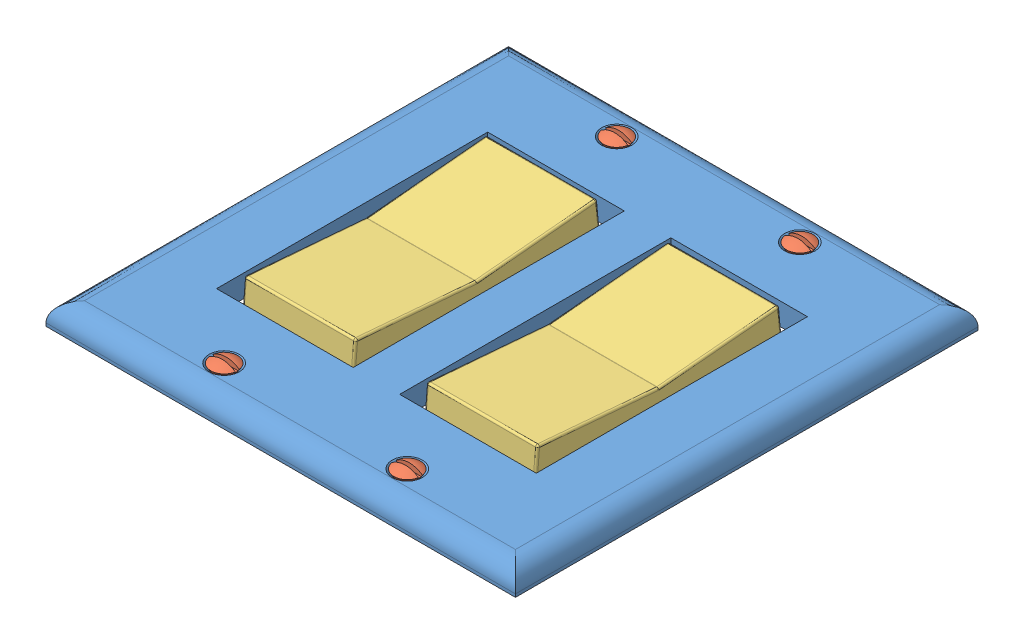
SolidWorks assembly rocker-switch, configuration Default. Lengths in mm.
Overall size (116 20.38 114.3).
7 component instances, 3 part files, 17 mates.
Components (placement in the parent):
- switchplate-1: switchplate [Default] at (-25.7009 60.0885 119.6547) size (116 5.5 114.3)
- screw-1: screw [Default] at (5.0495 56.6846 195.5169) x (0 -1 0) z (0 0 1) size (13.64 6.52 6.6)
- screw-2: screw [Default] at (-40.2005 56.6846 195.5169) x (0 -1 0) z (0 0 1) size (13.64 6.52 6.6)
- screw-3: screw [Default] at (5.0495 56.6846 98.5169) x (0 -1 0) z (0 0 1) size (13.64 6.52 6.6)
- screw-4: screw [Default] at (-40.2005 56.6846 98.5169) x (0 -1 0) z (0 0 1) size (13.64 6.52 6.6)
- rocker-3: rocker [Default] at (-8.7005 68.2721 117.0828) x (0 0.089515 -0.995986) z (1 0 0) size (60.87 12.79 27.5)
- rocker-4: rocker [Default] at (-26.4505 68.0995 176.5789) x (0 0.083761 0.996486) z (-1 0 0) size (60.87 12.79 27.5)
Mates (geometry in assembly coordinates):
- Distance1: distance = 15 mm: plane of ? through (-48.2755 80.5885 104.57) normal (0 1 0); plane of switchplate-1 through (-25.7009 65.5885 119.6547) normal (0 1 0)
- Distance2: distance = 1.8 mm anti-aligned: plane of switchplate-1 through (-23.3255 65.5885 113.3318) normal (-1 0 0); plane of ? through (-48.2755 67.6218 104.57) normal (1 0 0)
- Distance3: distance = 1.8 mm: plane of ? through (-9.1755 67.6218 145.4487) normal (-1 0 0); plane of switchplate-1 through (-11.8255 65.5885 119.6547) normal (1 0 0)
- Distance4: distance = 15 mm: plane of ? through (-9.1755 80.5885 145.4487) normal (0 1 0); plane of switchplate-1 through (-25.7009 65.5885 119.6547) normal (0 1 0)
- Concentric1: concentric aligned: cylinder of Double Switchplate-1 through (-40.2005 65.5885 195.3318) axis (0 -1 0) radius 2.25; cone of screw-2 through (4.7458 63.5841 195.3318) axis (0 -1 0)
- Coincident5: coincident anti-aligned: plane of Double Switchplate-1 through (-25.7009 65.5885 119.6547) normal (0 1 0); circle of Screw-2
- Concentric2: concentric aligned: cylinder of Double Switchplate-1 through (5.0495 65.5885 195.3318) axis (0 -1 0) radius 2.25; cone of Screw-1 through (5.0495 63.0885 195.3318) axis (0 -1 0)
- Concentric3: concentric aligned: cylinder of Double Switchplate-1 through (-40.2005 65.5885 98.3318) axis (0 -1 0) radius 2.25; cone of Screw-4 through (-40.2005 63.0885 98.3318) axis (0 -1 0)
- Concentric4: concentric aligned: cylinder of Double Switchplate-1 through (5.0495 65.5885 98.3318) axis (0 -1 0) radius 2.25; cone of Screw-3 through (5.0495 63.0885 98.3318) axis (0 -1 0)
- Coincident6: coincident anti-aligned: plane of Double Switchplate-1 through (-25.7009 65.5885 119.6547) normal (0 1 0); circle of Screw-3
- Coincident7: coincident anti-aligned: plane of Double Switchplate-1 through (-25.7009 65.5885 119.6547) normal (0 1 0); circle of Screw-1
- Coincident8: coincident anti-aligned: plane of Double Switchplate-1 through (-25.7009 65.5885 119.6547) normal (0 1 0); circle of Screw-4
- Distance5: distance = 3.125 mm anti-aligned: plane of Switch Rocker-3 through (18.7995 68.2721 117.0828) normal (1 0 0); plane of Double Switchplate-1 through (21.9245 65.5885 119.6547) normal (-1 0 0)
- Distance6: distance = 3.125 mm anti-aligned: plane of Switch Rocker-4 through (-26.4505 68.0995 176.5789) normal (1 0 0); plane of Double Switchplate-1 through (-23.3255 65.5885 113.3318) normal (-1 0 0)
- Tangent1: tangent anti-aligned: plane of Double Switchplate-1 through (-25.7009 65.5885 119.6547) normal (0 1 0); cylinder of Switch Rocker-4 through (-53.9505 66.0885 146.686) axis (-1 0 0) radius 0.5
- Tangent2: tangent anti-aligned: plane of Double Switchplate-1 through (-25.7009 65.5885 119.6547) normal (0 1 0); cylinder of Switch Rocker-3 through (18.7995 66.0885 146.9636) axis (1 0 0) radius 0.5
- Parallel1: parallel anti-aligned: plane of screw-1 through (1.7495 65.1623 195.8318) normal (0 0 -1); plane of screw-2 through (-43.5005 65.1623 194.8318) normal (0 0 1)
